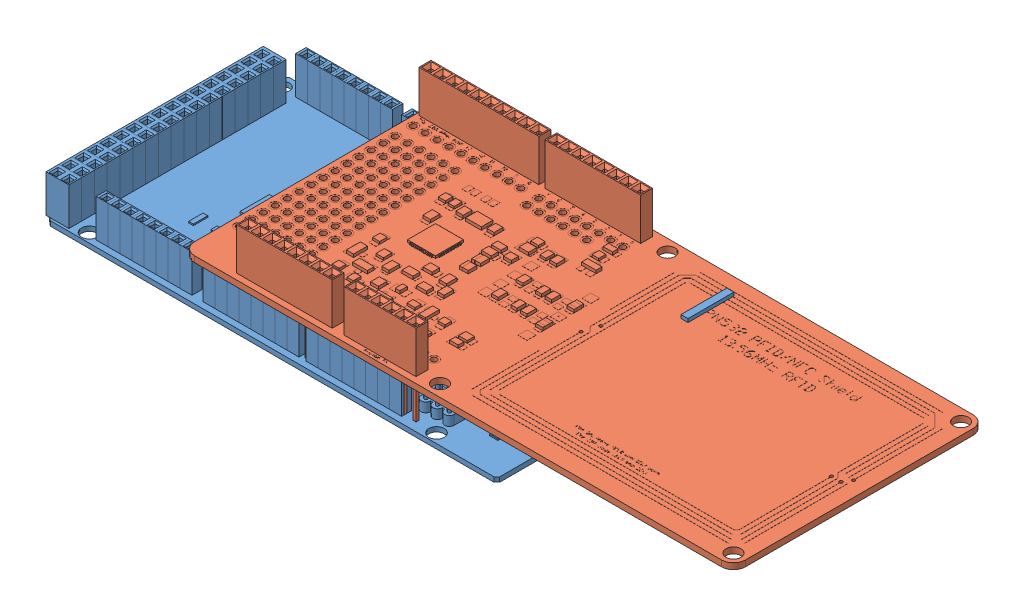
SolidWorks assembly ensamblearduino, configuration Predeterminado. Lengths in mm.
Overall size (149.68 19.81 53.34).
2 component instances, 2 part files, 2 mates.
Components (placement in the parent):
- ArduinoMega-1: ArduinoMega [Predeterminado] at (29.0981 79.1507 45.2548) size (100 11.65 51.63)
- NFC_shield-2: NFC_shield [Default] at (70.3559 75.4507 45.2372) size (116.84 18.41 53.34)
Mates (geometry in assembly coordinates):
- Coincidente5: coincident: plane of ArduinoMega-1 through (15.3879 88.1507 69.6847) normal (0 0 -1); plane of NFC_shield-2 through (23.0484 79.8957 69.6847) normal (0 0 1)
- Coincidente6: coincident: plane of ArduinoMega-1 through (51.7781 88.1507 45.2548) normal (0 1 0); plane of NFC_shield-2 through (70.3559 88.1507 45.2372) normal (0 -1 0)
